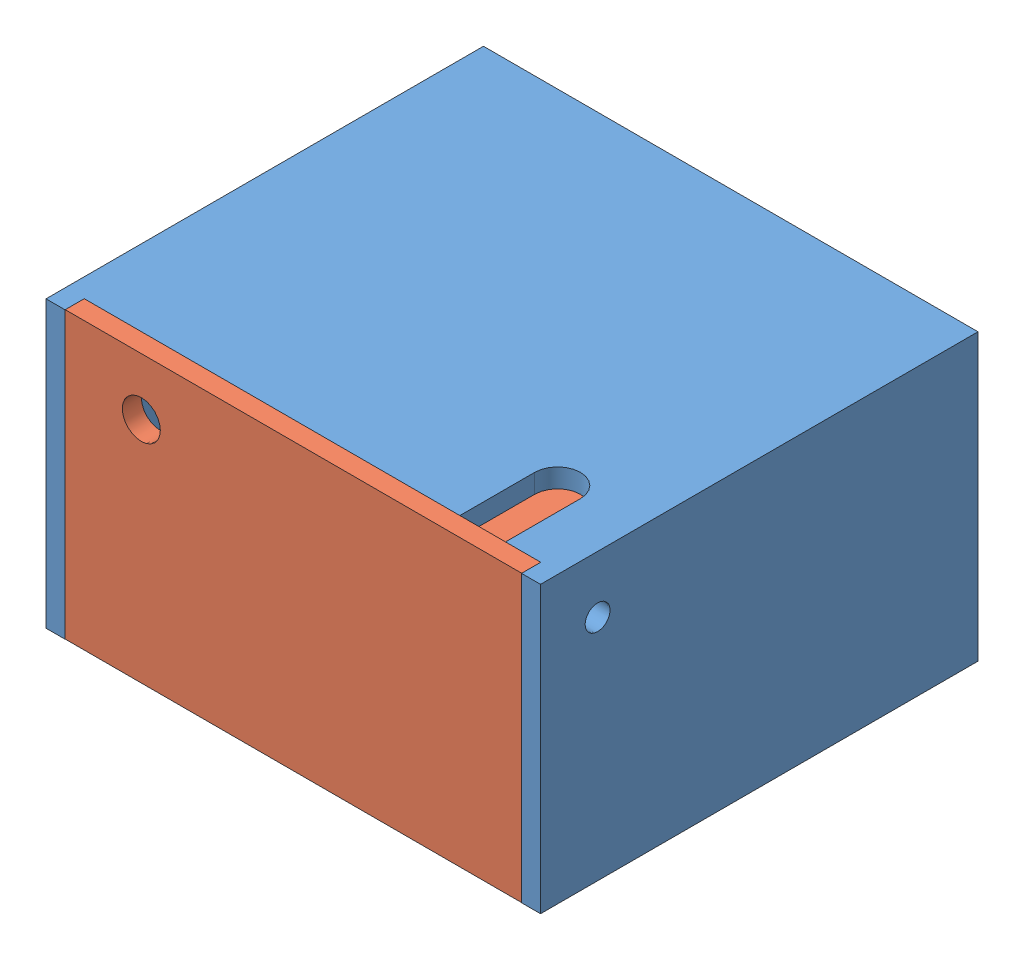
SolidWorks assembly Radio Box Assembly, configuration Default. Lengths in mm.
Overall size (82.55 47.62 73.03).
10 component instances, 4 part files, 26 mates.
Components (placement in the parent):
- Radio Box Base-1: Radio Box Base [Default] at (20.5784 25.6361 68.1824) size (82.55 47.62 73.03)
- Radio Box Insert-1: Radio Box Insert [Default] at (20.5784 46.2736 99.8979) size (76.2 47.62 69.85)
- #8-32 Hex Nut-1: #8-32 Hex Nut [Default] at (20.5766 35.1643 32.4292) x (0.866025 -0.5 0) z (0 0 1) size (8.73 10.08 3.61)
- #8-32 Hex Nut-2: #8-32 Hex Nut [Default] at (54.7097 60.5648 93.5479) x (0 -0.866025 0.5) z (1 0 0) size (8.73 10.08 3.61)
- #8-32 Hex Nut-3: #8-32 Hex Nut [Default] at (-13.5528 60.5648 93.5479) x (0 0.866025 -0.5) z (-1 0 0) size (8.73 10.08 3.61)
- 91780A029_ALUM FEM THRDED HEX STANDOFF-1: 91780A029_ALUM FEM THRDED HEX STANDOFF [91780A029] at (52.4935 31.1923 94.6782) x (0.866025 0 0.5) z (0 -1 0) size (3.17 3.67 11.52)
- 91780A029_ALUM FEM THRDED HEX STANDOFF-2: 91780A029_ALUM FEM THRDED HEX STANDOFF [91780A029] at (52.4935 31.1923 41.643) x (0.866025 0 -0.5) z (0 -1 0) size (3.17 3.67 11.52)
- 91780A029_ALUM FEM THRDED HEX STANDOFF-3: 91780A029_ALUM FEM THRDED HEX STANDOFF [91780A029] at (-11.3367 31.1923 72.123) x (0 0 1) z (0 -1 0) size (3.17 3.67 11.52)
- 91780A029_ALUM FEM THRDED HEX STANDOFF-4: 91780A029_ALUM FEM THRDED HEX STANDOFF [91780A029] at (13.4283 31.1923 94.348) x (0.866025 0 -0.5) z (0 -1 0) size (3.17 3.67 11.52)
- 91780A029_ALUM FEM THRDED HEX STANDOFF-5: 91780A029_ALUM FEM THRDED HEX STANDOFF [91780A029] at (-11.3367 31.1923 41.643) x (0 0 1) z (0 -1 0) size (3.17 3.67 11.52)
Mates (geometry in assembly coordinates):
- Coincident1: coincident anti-aligned: plane of Radio Box Base-1 through (58.6784 66.9111 103.1074) normal (-1 0 0); plane of Radio Box Insert-1 through (58.6784 22.4611 103.0729) normal (1 0 0)
- Coincident2: coincident anti-aligned: plane of Radio Box Base-1 through (20.5784 25.6361 68.1824) normal (0 1 0); plane of Radio Box Insert-1 through (58.6784 25.6361 33.2229) normal (0 -1 0)
- Coincident6: coincident aligned: plane of Radio Box Insert-1 through (58.6784 22.4611 103.0729) normal (1 0 0); plane of #8-32 Hex Nut-2 through (58.6784 60.5648 93.5479) normal (1 0 0)
- Coincident7: coincident anti-aligned: plane of Radio Box Insert-1 through (-17.5216 63.0834 89.1791) normal (0 -0.866025 0.5); plane of #8-32 Hex Nut-2 through (58.6784 63.0853 89.1823) normal (0 0.866025 -0.5)
- Coincident8: coincident anti-aligned: plane of Radio Box Insert-1 through (-17.5216 65.6057 93.5479) normal (0 -0.866025 -0.5); plane of #8-32 Hex Nut-2 through (58.6784 65.6057 93.5479) normal (0 0.866025 0.5)
- Coincident9: coincident aligned: plane of Radio Box Insert-1 through (-17.5216 22.4611 103.0729) normal (-1 0 0); plane of #8-32 Hex Nut-3 through (-17.5216 60.5648 93.5479) normal (-1 0 0)
- Coincident10: coincident anti-aligned: plane of Radio Box Insert-1 through (-17.5216 63.0834 89.1791) normal (0 -0.866025 0.5); plane of #8-32 Hex Nut-3 through (-17.5216 65.6057 93.5479) normal (0 0.866025 -0.5)
- Coincident11: coincident anti-aligned: plane of Radio Box Insert-1 through (-17.5216 65.6057 93.5479) normal (0 -0.866025 -0.5); plane of #8-32 Hex Nut-3 through (-17.5216 63.0853 97.9136) normal (0 0.866025 0.5)
- Coincident12: coincident aligned: plane of Radio Box Insert-1 through (20.5784 46.2736 33.2229) normal (0 0 -1); plane of #8-32 Hex Nut-1 through (20.5766 35.1643 33.2229) normal (0 0 -1)
- Coincident13: coincident anti-aligned: plane of Radio Box Insert-1 through (18.0561 39.5299 36.3979) normal (0 -1 0); plane of #8-32 Hex Nut-1 through (23.0971 39.5299 36.3979) normal (0 1 0)
- Coincident14: coincident anti-aligned: plane of Radio Box Insert-1 through (15.5338 35.1611 36.3979) normal (0.866025 -0.5 0); plane of #8-32 Hex Nut-1 through (18.0561 39.5299 36.3979) normal (-0.866025 0.5 0)
- Coincident16: coincident aligned: plane of Radio Box Insert-1 through (58.6784 25.6361 33.2229) normal (0 -1 0); plane of 91780A029_ALUM FEM THRDED HEX STANDOFF-2 through (53.4101 25.6361 43.2305) normal (0 -1 0)
- Coincident17: coincident anti-aligned: plane of Radio Box Insert-1 through (51.577 25.6361 40.0555) normal (0.866025 0 0.5); plane of 91780A029_ALUM FEM THRDED HEX STANDOFF-2 through (50.6604 25.6361 41.643) normal (-0.866025 0 -0.5)
- Coincident18: coincident anti-aligned: plane of Radio Box Insert-1 through (50.6604 25.6361 41.643) normal (0.866025 0 -0.5); plane of 91780A029_ALUM FEM THRDED HEX STANDOFF-2 through (51.577 25.6361 43.2305) normal (-0.866025 0 0.5)
- Coincident19: coincident aligned: plane of Radio Box Insert-1 through (58.6784 25.6361 33.2229) normal (0 -1 0); plane of 91780A029_ALUM FEM THRDED HEX STANDOFF-1 through (51.577 25.6361 96.2657) normal (0 -1 0)
- Coincident20: coincident anti-aligned: plane of Radio Box Insert-1 through (51.577 25.6361 93.0907) normal (0.866025 0 0.5); plane of 91780A029_ALUM FEM THRDED HEX STANDOFF-1 through (50.6604 25.6361 94.6782) normal (-0.866025 0 -0.5)
- Coincident21: coincident anti-aligned: plane of Radio Box Insert-1 through (50.6604 25.6361 94.6782) normal (0.866025 0 -0.5); plane of 91780A029_ALUM FEM THRDED HEX STANDOFF-1 through (51.577 25.6361 96.2657) normal (-0.866025 0 0.5)
- Coincident22: coincident aligned: plane of Radio Box Insert-1 through (58.6784 25.6361 33.2229) normal (0 -1 0); plane of 91780A029_ALUM FEM THRDED HEX STANDOFF-3 through (-13.1698 25.6361 72.123) normal (0 -1 0)
- Coincident23: coincident aligned: plane of Radio Box Insert-1 through (58.6784 25.6361 33.2229) normal (0 -1 0); plane of 91780A029_ALUM FEM THRDED HEX STANDOFF-5 through (-13.1698 25.6361 41.643) normal (0 -1 0)
- Coincident25: coincident aligned: plane of Radio Box Insert-1 through (58.6784 25.6361 33.2229) normal (0 -1 0); plane of 91780A029_ALUM FEM THRDED HEX STANDOFF-4 through (14.3449 25.6361 95.9355) normal (0 -1 0)
- Coincident26: coincident anti-aligned: plane of Radio Box Insert-1 through (11.5952 25.6361 94.348) normal (0.866025 0 -0.5); plane of 91780A029_ALUM FEM THRDED HEX STANDOFF-4 through (12.5118 25.6361 95.9355) normal (-0.866025 0 0.5)
- Coincident27: coincident anti-aligned: plane of Radio Box Insert-1 through (12.5118 25.6361 95.9355) normal (0 0 -1); plane of 91780A029_ALUM FEM THRDED HEX STANDOFF-4 through (14.3449 25.6361 95.9355) normal (0 0 1)
- Coincident28: coincident anti-aligned: plane of Radio Box Insert-1 through (-13.1698 25.6361 72.123) normal (0.866025 0 -0.5); plane of 91780A029_ALUM FEM THRDED HEX STANDOFF-3 through (-12.2532 25.6361 73.7105) normal (-0.866025 0 0.5)
- Coincident29: coincident anti-aligned: plane of Radio Box Insert-1 through (-12.2532 25.6361 70.5355) normal (0.866025 0 0.5); plane of 91780A029_ALUM FEM THRDED HEX STANDOFF-3 through (-13.1698 25.6361 72.123) normal (-0.866025 0 -0.5)
- Coincident30: coincident anti-aligned: plane of Radio Box Insert-1 through (-13.1698 25.6361 41.643) normal (0.866025 0 -0.5); plane of 91780A029_ALUM FEM THRDED HEX STANDOFF-5 through (-12.2532 25.6361 43.2305) normal (-0.866025 0 0.5)
- Coincident32: coincident anti-aligned: plane of Radio Box Insert-1 through (-12.2532 25.6361 40.0555) normal (0.866025 0 0.5); plane of 91780A029_ALUM FEM THRDED HEX STANDOFF-5 through (-13.1698 25.6361 41.643) normal (-0.866025 0 -0.5)
